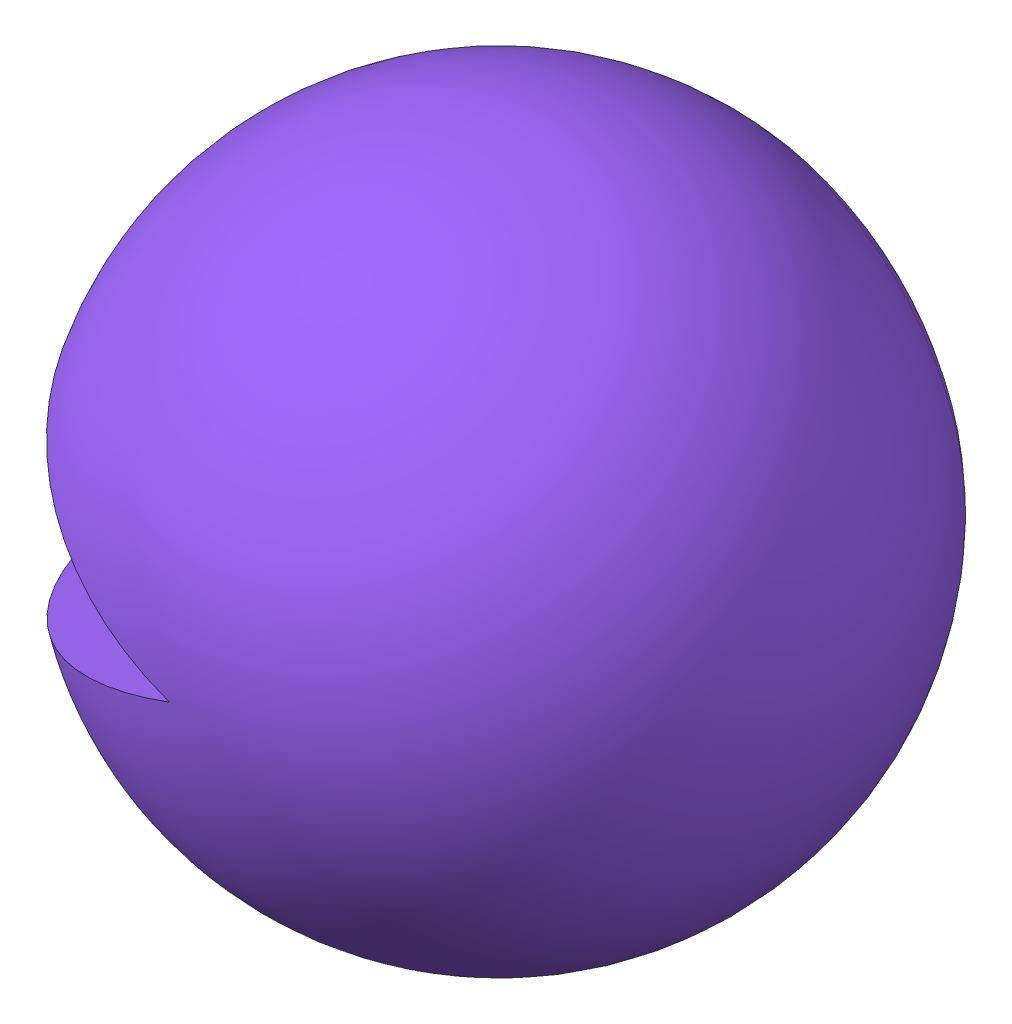
SolidWorks assembly GR6150-2500 机器人数模（R侧）-2016 V1.0, configuration 默认. Lengths in mm.
Overall size (6406.82 6406.82 4713.11).
8 component instances, 8 part files, 27 mates.
Components (placement in the parent):
- 复件 底座^GR6150-2500 机器人数模（R侧）-2016 V1.0-4: 复件 底座^GR6150-2500 机器人数模（R侧）-2016 V1.0 [默认] at (-75.5764 34.0027 647.3326) x (-1 0 0) z (0 1 0) size (675 510 660) (virtual)
- 复件 转座^GR6150-2500 机器人数模（R侧）-2016 V1.0-2: 复件 转座^GR6150-2500 机器人数模（R侧）-2016 V1.0 [默认] at (65.5435 -35.1938 562.2241) x (1 0 0) z (0 -1 0) size (545.36 673.77 602.58) (virtual)
- 复件 大臂^GR6150-2500 机器人数模（R侧）-2016 V1.0-1: 复件 大臂^GR6150-2500 机器人数模（R侧）-2016 V1.0 [默认] at (65.5435 -35.1938 562.2241) x (1 0 0) z (0 -1 0) size (480 1380 306.5) (virtual)
- 复件 工艺臂^GR6150-2500 机器人数模（R侧）-2016 V1.0-4: 复件 工艺臂^GR6150-2500 机器人数模（R侧）-2016 V1.0 [默认] at (-65.5435 -35.1938 3037.7759) x (-1 0 0) z (0 -1 0) size (1732.58 387.05 459.55) (virtual)
- 复件 J4^GR6150-2500 机器人数模（R侧）-2016 V1.0-1: 复件 J4^GR6150-2500 机器人数模（R侧）-2016 V1.0 [默认] at (131.4749 40.1938 201.334) x (-0.979925 0 0.199368) z (0 1 0) size (212.05 184.72 176) (virtual)
- 复件 J5^GR6150-2500 机器人数模（R侧）-2016 V1.0-1: 复件 J5^GR6150-2500 机器人数模（R侧）-2016 V1.0 [默认] at (131.4749 40.1933 201.3339) x (-0.979925 0 0.199368) z (0 1 0) size (162.94 140.06 134.71) (virtual)
- 复件 法兰^GR6150-2500 机器人数模（R侧）-2016 V1.0-2: 复件 法兰^GR6150-2500 机器人数模（R侧）-2016 V1.0 [默认] at (1632.1092 5 1698.0434) x (-1 0 0) z (0 1 0) size (32 114.86 115) (virtual)
- 复件 运动范围图^GR6150-2500 机器人数模（R侧）-2016 V1.0-2: 复件 运动范围图^GR6150-2500 机器人数模（R侧）-2016 V1.0 [默认] at (0 0 800) x (0.940762 -0.339066 0) z (-0.339066 -0.940762 0) size (5006 4713.11 5006) (virtual)
Mates (geometry in assembly coordinates):
- 重合1: coincident anti-aligned: plane of 复件 底座^GR6150-2500 机器人数模（R侧）-2016 V1.0-4 through (200 -258.1628 0) normal (0 0 -1); plane of assembly through (0 0 0) normal (0 0 1)
- 距离1: distance = 330 mm anti-aligned: plane of 复件 底座^GR6150-2500 机器人数模（R侧）-2016 V1.0-4 through (-450 -330 0) normal (0 -1 0); plane of assembly through (0 0 0) normal (0 1 0)
- 距离2: distance = 450 mm anti-aligned: plane of 复件 底座^GR6150-2500 机器人数模（R侧）-2016 V1.0-4 through (-450 -250 0) normal (-1 0 0); plane of assembly through (0 0 0) normal (1 0 0)
- 同心1: concentric anti-aligned: cylinder of 复件 转座^GR6150-2500 机器人数模（R侧）-2016 V1.0-2 through (0 0 475) axis (0 0 -1) radius 225; cone of 复件 底座^GR6150-2500 机器人数模（R侧）-2016 V1.0-4 through (0 0 420.6757) axis (0 0 1)
- 距离3: distance = 64.5 mm anti-aligned: plane of 复件 底座^GR6150-2500 机器人数模（R侧）-2016 V1.0-4 through (296.9703 122.602 390.5) normal (0 0 1); plane of 复件 转座^GR6150-2500 机器人数模（R侧）-2016 V1.0-2 through (-255 180 455) normal (0 0 -1)
- LimitAngle1: limit planar angle = 0 rad aligned: plane of 复件 转座^GR6150-2500 机器人数模（R侧）-2016 V1.0-2 through (4 217.5 425) normal (-1 0 0); plane of 复件 底座^GR6150-2500 机器人数模（R侧）-2016 V1.0-4 through (4 -330.0011 415.5) normal (-1 0 0)
- 转座回归初始位置: parallel aligned: plane of 复件 转座^GR6150-2500 机器人数模（R侧）-2016 V1.0-2 through (-4 217.5 410) normal (1 0 0); plane of 复件 底座^GR6150-2500 机器人数模（R侧）-2016 V1.0-4 through (-4 -330.0011 415.5) normal (1 0 0)
- 同心2: concentric anti-aligned: cylinder of 复件 转座^GR6150-2500 机器人数模（R侧）-2016 V1.0-2 through (0 -90.1642 800) axis (0 1 0) radius 255; cylinder of 复件 大臂^GR6150-2500 机器人数模（R侧）-2016 V1.0-1 through (0 185 800) axis (0 -1 0) radius 224.75
- 距离4: distance = 5 mm anti-aligned: plane of 复件 大臂^GR6150-2500 机器人数模（R侧）-2016 V1.0-1 through (-242.88 185 557.12) normal (0 -1 0); plane of 复件 转座^GR6150-2500 机器人数模（R侧）-2016 V1.0-2 through (255 180 455) normal (0 1 0)
- LimitAngle2: limit planar angle = 0 rad aligned: plane of 复件 大臂^GR6150-2500 机器人数模（R侧）-2016 V1.0-1 through (-4 195.6 1079.8817) normal (1 0 0); plane of 复件 转座^GR6150-2500 机器人数模（R侧）-2016 V1.0-2 through (-4 171.85 1067.7716) normal (1 0 0)
- 大臂回归初始位置: parallel aligned: plane of 复件 转座^GR6150-2500 机器人数模（R侧）-2016 V1.0-2 through (4 156.85 1067.7716) normal (-1 0 0); plane of 复件 大臂^GR6150-2500 机器人数模（R侧）-2016 V1.0-1 through (4 195.6 1067.8817) normal (-1 0 0)
- 同心3: concentric aligned: cylinder of 复件 大臂^GR6150-2500 机器人数模（R侧）-2016 V1.0-1 through (0 379.6 1800) axis (0 -1 0) radius 140; cylinder of 复件 工艺臂^GR6150-2500 机器人数模（R侧）-2016 V1.0-4 through (0 215 1800) axis (0 -1 0) radius 140
- 距离5: distance = 0.4 mm anti-aligned: plane of 复件 工艺臂^GR6150-2500 机器人数模（R侧）-2016 V1.0-4 through (141.68 215 1658.32) normal (0 1 0); plane of 复件 大臂^GR6150-2500 机器人数模（R侧）-2016 V1.0-1 through (138.9198 214.6 1658.32) normal (0 -1 0)
- LimitAngle3: limit planar angle = 0 rad anti-aligned: plane of 复件 大臂^GR6150-2500 机器人数模（R侧）-2016 V1.0-1 through (-159.3742 218.1 1802) normal (0 0 -1); plane of 复件 工艺臂^GR6150-2500 机器人数模（R侧）-2016 V1.0-4 through (159.95 214 1796) normal (0 0 1)
- 工艺臂回归初始位置: parallel anti-aligned: plane of 复件 大臂^GR6150-2500 机器人数模（R侧）-2016 V1.0-1 through (-159.3742 233.1 1794) normal (0 0 1); plane of 复件 工艺臂^GR6150-2500 机器人数模（R侧）-2016 V1.0-4 through (170 214 1804) normal (0 0 -1)
- 同心4: concentric aligned: cylinder of 复件 J4^GR6150-2500 机器人数模（R侧）-2016 V1.0-1 through (1457.4865 5 1800) axis (1 0 0) radius 80; cylinder of 复件 工艺臂^GR6150-2500 机器人数模（R侧）-2016 V1.0-4 through (1415.5 5 1800) axis (1 0 0) radius 104
- 距离8: distance = 7 mm anti-aligned: plane of 复件 工艺臂^GR6150-2500 机器人数模（R侧）-2016 V1.0-4 through (1433 -69.0638 1928.2822) normal (1 0 0); plane of 复件 J4^GR6150-2500 机器人数模（R侧）-2016 V1.0-1 through (1440 5 1883.5) normal (-1 0 0)
- J4回归初始位置: concentric anti-aligned: cylinder of 复件 J4^GR6150-2500 机器人数模（R侧）-2016 V1.0-1 through (1455 5 1895) axis (-1 0 0) radius 4; cylinder of 复件 工艺臂^GR6150-2500 机器人数模（R侧）-2016 V1.0-4 through (1430 5 1895) axis (1 0 0) radius 4
- 同心6: concentric aligned: cylinder of 复件 J4^GR6150-2500 机器人数模（R侧）-2016 V1.0-1 through (1527.4544 5 1732.812) axis (0.34202 0 -0.939693) radius 77; cylinder of 复件 J5^GR6150-2500 机器人数模（R侧）-2016 V1.0-1 through (1540.1092 5 1698.0434) axis (0.34202 0 -0.939693) radius 60
- 距离6: distance = 10 mm anti-aligned: plane of 复件 J5^GR6150-2500 机器人数模（R侧）-2016 V1.0-1 through (1556.9235 5 1754.1796) normal (-0.34202 0 0.939693); plane of 复件 J4^GR6150-2500 机器人数模（R侧）-2016 V1.0-1 through (1527.4544 82 1732.812) normal (0.34202 0 -0.939693)
- J5回归初始位置: parallel aligned: plane of 复件 J4^GR6150-2500 机器人数模（R侧）-2016 V1.0-1 through (1455 5 1886) normal (1 0 0); plane of 复件 J5^GR6150-2500 机器人数模（R侧）-2016 V1.0-1 through (1615.1092 5 1760.0434) normal (1 0 0)
- 同心7: concentric aligned: cylinder of 复件 J5^GR6150-2500 机器人数模（R侧）-2016 V1.0-1 through (1615.1092 5 1698.0434) axis (1 0 0) radius 62; cylinder of 复件 法兰^GR6150-2500 机器人数模（R侧）-2016 V1.0-2 through (1624.1092 5 1698.0434) axis (1 0 0) radius 46
- 距离7: distance = 1 mm anti-aligned: plane of 复件 法兰^GR6150-2500 机器人数模（R侧）-2016 V1.0-2 through (1616.1092 -53.19 1639.8542) normal (-1 0 0); plane of 复件 J5^GR6150-2500 机器人数模（R侧）-2016 V1.0-1 through (1615.1092 5 1760.0434) normal (1 0 0)
- 法兰回归初始位置: concentric aligned: cylinder of 复件 J5^GR6150-2500 机器人数模（R侧）-2016 V1.0-1 through (1613.1092 5 1755.0434) axis (1 0 0) radius 4; cylinder of 复件 法兰^GR6150-2500 机器人数模（R侧）-2016 V1.0-2 through (1616.1092 5 1755.0434) axis (1 0 0) radius 4
- 同心9: concentric: sphere of 复件 运动范围图^GR6150-2500 机器人数模（R侧）-2016 V1.0-2; cylinder of 复件 底座^GR6150-2500 机器人数模（R侧）-2016 V1.0-4 through (0 0 351.5) axis (0 0 1) radius 224.75
- 重合3: coincident anti-aligned: plane of 复件 底座^GR6150-2500 机器人数模（R侧）-2016 V1.0-4 through (200 -258.1628 0) normal (0 0 -1); plane of 复件 运动范围图^GR6150-2500 机器人数模（R侧）-2016 V1.0-2 through (0 0 0) normal (0 0 1)
- 角度1: planar angle = 0.003142 rad anti-aligned: plane of 复件 运动范围图^GR6150-2500 机器人数模（R侧）-2016 V1.0-2; plane of 复件 底座^GR6150-2500 机器人数模（R侧）-2016 V1.0-4 through (-75.5764 34.0027 647.3326) normal (0 1 0)
